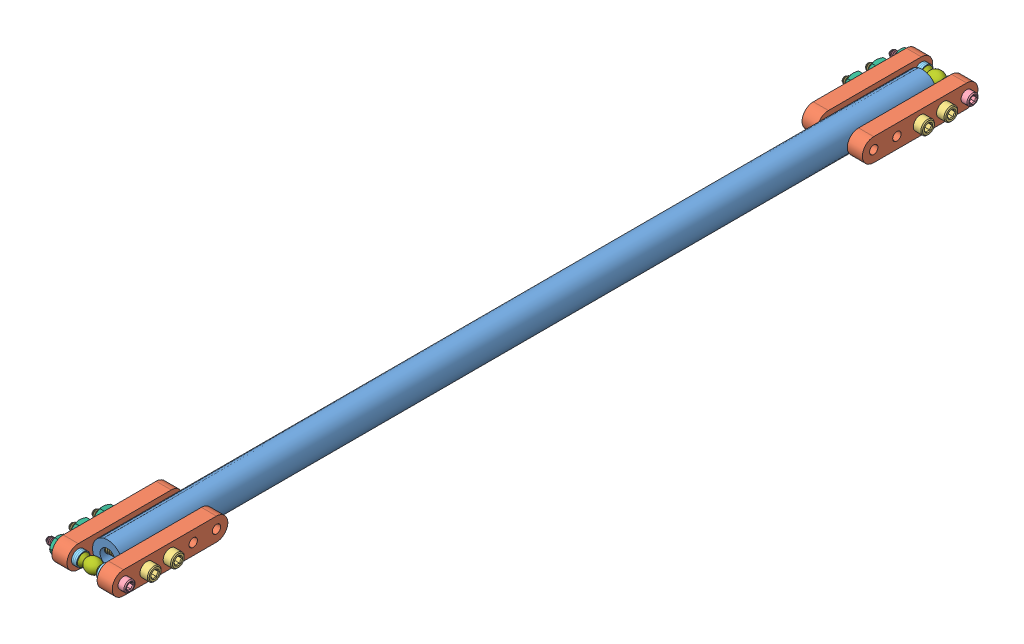
SolidWorks assembly Diff Pivot Top, configuration Default. Lengths in mm.
Overall size (35.29 12.7 364.36).
31 component instances, 7 part files, 34 mates.
Components (placement in the parent):
- 13.5 Inch Aluminum Rod-1: 13.5 Inch Aluminum Rod [Default] at (112.518 164.0173 110.0632) size (12.7 12.7 342.9)
- 5 Hole Aluminum Beam-1: 5 Hole Aluminum Beam [Default] at (106.168 164.0173 439.3742) x (0 0 -1) z (0 1 0) size (48.64 6.35 9.53)
- 5 Hole Aluminum Beam-2: 5 Hole Aluminum Beam [Default] at (125.218 164.0173 439.3742) x (0 0 -1) z (0 1 0) size (48.64 6.35 9.53)
- 6-32_SHCS-1: 6-32_SHCS [6-32 SHCS X 1.250] at (93.468 164.0173 449.1532) x (0 0 -1) z (1 0 0) size (5.74 5.74 35.26)
- 6-32_SHCS-2: 6-32_SHCS [6-32 SHCS X 1.250] at (93.468 164.0173 439.3742) x (0 0 -1) z (1 0 0) size (5.74 5.74 35.26)
- 4-40_SHCS-1: 4-40_SHCS [4-40 SHCS X 1.250] at (93.468 164.0173 458.9322) x (0 -0.924225 -0.381849) z (1 0 0) size (4.65 4.65 34.63)
- 4-40 Washer-1: 4-40 Washer [Default] at (118.1568 164.0173 458.9322) x (0 -1 0) z (0 0 1) size (5.71 0.71 5.71)
- 4-40 Washer-2: 4-40 Washer [Default] at (118.1568 164.0173 458.9322) x (0 1 0) z (0 0 1) size (5.71 0.71 5.71)
- 4-40 Washer-3: 4-40 Washer [Default] at (116.7344 164.0173 458.9322) x (0 -1 0) z (0 0 1) size (5.71 0.71 5.71)
- 4-40 Washer-4: 4-40 Washer [Default] at (106.168 164.0173 458.9322) x (0 -1 0) z (0 0 1) size (5.71 0.71 5.71)
- 4-40 Washer-5: 4-40 Washer [Default] at (107.5904 164.0173 458.9322) x (0 -1 0) z (0 0 1) size (5.71 0.71 5.71)
- 4-40 Washer-6: 4-40 Washer [Default] at (106.8792 164.0173 458.9322) x (0 -1 0) z (0 0 1) size (5.71 0.71 5.71)
- hex_nut-1: hex_nut [#6-32] at (99.818 164.0173 449.1532) x (0 1 0) z (0 0 1) size (7.92 2.9 10.06)
- hex_nut-2: hex_nut [#6-32] at (99.818 164.0173 439.3742) x (0 0.381849 -0.924225) z (0 0.924225 0.381849) size (7.92 2.9 10.06)
- hex_nut-3: hex_nut [#4-40] at (99.818 164.0173 458.9322) x (0 -0.381849 0.924225) z (0 -0.924225 -0.381849) size (6.35 2.49 8.06)
- 5 Hole Aluminum Beam-3: 5 Hole Aluminum Beam [Default] at (99.818 164.0173 123.6522) x (0 0 1) z (0 1 0) size (48.64 6.35 9.53)
- 5 Hole Aluminum Beam-4: 5 Hole Aluminum Beam [Default] at (118.868 164.0173 123.6522) x (0 0 1) z (0 1 0) size (48.64 6.35 9.53)
- 6-32_SHCS-3: 6-32_SHCS [6-32 SHCS X 1.250] at (93.468 164.0173 113.8732) x (0 0 -1) z (1 0 0) size (5.74 5.74 35.26)
- 6-32_SHCS-4: 6-32_SHCS [6-32 SHCS X 1.250] at (93.468 164.0173 123.6522) x (0 0 -1) z (1 0 0) size (5.74 5.74 35.26)
- 4-40_SHCS-2: 4-40_SHCS [4-40 SHCS X 1.250] at (93.468 164.0173 104.0942) x (0 0.924225 -0.381849) z (1 0 0) size (4.65 4.65 34.63)
- 4-40 Washer-7: 4-40 Washer [Default] at (118.1568 164.0173 104.0942) x (0 -1 0) z (0 0 1) size (5.71 0.71 5.71)
- 4-40 Washer-8: 4-40 Washer [Default] at (118.1568 164.0173 104.0942) x (0 1 0) z (0 0 1) size (5.71 0.71 5.71)
- 4-40 Washer-9: 4-40 Washer [Default] at (116.7344 164.0173 104.0942) x (0 -1 0) z (0 0 1) size (5.71 0.71 5.71)
- 4-40 Washer-10: 4-40 Washer [Default] at (106.168 164.0173 104.0942) x (0 -1 0) z (0 0 1) size (5.71 0.71 5.71)
- 4-40 Washer-11: 4-40 Washer [Default] at (107.5904 164.0173 104.0942) x (0 -1 0) z (0 0 1) size (5.71 0.71 5.71)
- 4-40 Washer-12: 4-40 Washer [Default] at (106.8792 164.0173 104.0942) x (0 -1 0) z (0 0 1) size (5.71 0.71 5.71)
- hex_nut-4: hex_nut [#6-32] at (99.818 164.0173 113.8732) x (0 1 0) z (0 0 1) size (7.92 2.9 10.06)
- hex_nut-5: hex_nut [#4-40] at (99.818 164.0173 104.0942) x (0 -0.381849 -0.924225) z (0 0.924225 -0.381849) size (6.35 2.49 8.06)
- hex_nut-6: hex_nut [#6-32] at (99.818 164.0173 123.6522) x (0 0.381849 0.924225) z (0 -0.924225 0.381849) size (7.92 2.9 10.06)
- Ball bearing-1: Ball bearing [Default] at (116.6455 164.0173 458.9322) x (0 1 0) z (0 0 1) size (5.73 8.26 5.73)
- Ball bearing-2: Ball bearing [Default] at (108.3905 164.0173 104.0942) x (0 -1 0) z (0 0 1) size (5.73 8.26 5.73)
Mates (geometry in assembly coordinates):
- Concentric3: concentric anti-aligned: cylinder of 13.5 Inch Aluminum Rod-1 through (-65.282 164.0173 439.3742) axis (1 0 0) radius 1.905; cylinder of 5 Hole Aluminum Beam-2 through (118.868 164.0173 439.3742) axis (-1 0 0) radius 1.778
- Concentric4: concentric anti-aligned: cylinder of 13.5 Inch Aluminum Rod-1 through (-65.282 164.0173 439.3742) axis (1 0 0) radius 1.905; cylinder of 5 Hole Aluminum Beam-1 through (99.818 164.0173 439.3742) axis (-1 0 0) radius 1.778
- Concentric5: concentric anti-aligned: cylinder of 13.5 Inch Aluminum Rod-1 through (-65.282 164.0173 439.3742) axis (1 0 0) radius 1.905; cylinder of 6-32_SHCS-2 through (137.918 164.0173 439.3742) axis (-1 0 0) radius 2.8702
- Concentric6: concentric aligned: cylinder of 5 Hole Aluminum Beam-1 through (99.818 164.0173 439.3742) axis (-1 0 0) radius 1.778; cylinder of hex_nut-2 through (98.1544 164.0173 439.3742) axis (-1 0 0) radius 1.323
- Concentric7: concentric anti-aligned: cylinder of 13.5 Inch Aluminum Rod-1 through (-65.282 164.0173 449.1532) axis (1 0 0) radius 1.905; cylinder of 5 Hole Aluminum Beam-1 through (99.818 164.0173 449.1532) axis (-1 0 0) radius 1.778
- Concentric8: concentric anti-aligned: cylinder of 13.5 Inch Aluminum Rod-1 through (-65.282 164.0173 449.1532) axis (1 0 0) radius 1.905; cylinder of 5 Hole Aluminum Beam-2 through (118.868 164.0173 449.1532) axis (-1 0 0) radius 1.778
- Concentric9: concentric anti-aligned: cylinder of 13.5 Inch Aluminum Rod-1 through (-65.282 164.0173 449.1532) axis (1 0 0) radius 1.905; cylinder of 6-32_SHCS-1 through (137.918 164.0173 449.1532) axis (-1 0 0) radius 2.8702
- Concentric10: concentric aligned: cylinder of 13.5 Inch Aluminum Rod-1 through (-65.282 164.0173 449.1532) axis (1 0 0) radius 1.905; cone of hex_nut-1 through (97.5177 164.0173 449.1532) axis (1 0 0)
- Tangent1: tangent anti-aligned: cylinder of 13.5 Inch Aluminum Rod-1 through (112.518 164.0173 452.9632) axis (0 0 -1) radius 6.35; plane of 5 Hole Aluminum Beam-1 through (106.168 164.0173 458.9322) normal (1 0 0)
- Tangent3: tangent anti-aligned: cylinder of 13.5 Inch Aluminum Rod-1 through (112.518 164.0173 452.9632) axis (0 0 -1) radius 6.35; plane of 5 Hole Aluminum Beam-2 through (118.868 164.0173 458.9322) normal (-1 0 0)
- Coincident1: coincident aligned: plane of 6-32_SHCS-2 through (125.218 164.0173 439.3742) normal (-1 0 0); plane of 6-32_SHCS-1 through (125.218 164.0173 449.1532) normal (-1 0 0)
- Coincident2: coincident anti-aligned: plane of 6-32_SHCS-2 through (125.218 164.0173 439.3742) normal (-1 0 0); plane of 5 Hole Aluminum Beam-2 through (125.218 164.0173 458.9322) normal (1 0 0)
- Coincident3: coincident anti-aligned: plane of 5 Hole Aluminum Beam-1 through (99.818 164.0173 458.9322) normal (-1 0 0); plane of hex_nut-2 through (99.818 156.1613 440.4157) normal (1 0 0)
- Coincident4: coincident anti-aligned: plane of 5 Hole Aluminum Beam-1 through (99.818 164.0173 458.9322) normal (-1 0 0); plane of hex_nut-1 through (99.818 160.0549 442.2902) normal (1 0 0)
- Concentric12: concentric aligned: cylinder of 5 Hole Aluminum Beam-2 through (118.868 164.0173 458.9322) axis (-1 0 0) radius 1.778; cylinder of 4-40 Washer-2 through (117.4456 164.0173 458.9322) axis (-1 0 0) radius 1.4732
- Concentric13: concentric anti-aligned: cylinder of 5 Hole Aluminum Beam-2 through (118.868 164.0173 458.9322) axis (-1 0 0) radius 1.778; cylinder of 4-40 Washer-6 through (107.5904 164.0173 458.9322) axis (1 0 0) radius 1.4732
- Concentric14: concentric anti-aligned: cylinder of 5 Hole Aluminum Beam-2 through (118.868 164.0173 458.9322) axis (-1 0 0) radius 1.778; cylinder of 4-40 Washer-4 through (106.8792 164.0173 458.9322) axis (1 0 0) radius 1.4732
- Concentric15: concentric anti-aligned: cylinder of 5 Hole Aluminum Beam-2 through (118.868 164.0173 458.9322) axis (-1 0 0) radius 1.778; cylinder of 4-40 Washer-5 through (108.3016 164.0173 458.9322) axis (1 0 0) radius 1.4732
- Concentric16: concentric anti-aligned: cylinder of 5 Hole Aluminum Beam-2 through (118.868 164.0173 458.9322) axis (-1 0 0) radius 1.778; cylinder of 4-40 Washer-3 through (117.4456 164.0173 458.9322) axis (1 0 0) radius 1.4732
- Concentric17: concentric anti-aligned: cylinder of 5 Hole Aluminum Beam-2 through (118.868 164.0173 458.9322) axis (-1 0 0) radius 1.778; cylinder of 4-40 Washer-1 through (118.868 164.0173 458.9322) axis (1 0 0) radius 1.4732
- Concentric19: concentric aligned: cylinder of 5 Hole Aluminum Beam-2 through (118.868 164.0173 458.9322) axis (-1 0 0) radius 1.778; cylinder of hex_nut-3 through (98.1544 164.0173 458.9322) axis (-1 0 0) radius 1.0787
- Coincident5: coincident anti-aligned: plane of 5 Hole Aluminum Beam-2 through (125.218 164.0173 458.9322) normal (1 0 0); plane of 4-40_SHCS-1 through (125.218 164.0173 458.9322) normal (-1 0 0)
- Coincident6: coincident anti-aligned: plane of 5 Hole Aluminum Beam-1 through (99.818 164.0173 458.9322) normal (-1 0 0); plane of hex_nut-3 through (99.818 167.4057 460.3322) normal (1 0 0)
- Coincident7: coincident anti-aligned: plane of 4-40 Washer-4 through (106.8792 164.0173 458.9322) normal (1 0 0); plane of 4-40 Washer-6 through (106.8792 164.0173 458.9322) normal (-1 0 0)
- Coincident8: coincident aligned: circle of 4-40 Washer-5; plane of 4-40 Washer-6 through (107.5904 164.0173 458.9322) normal (1 0 0)
- Coincident9: coincident anti-aligned: plane of 4-40 Washer-1 through (118.1568 164.0173 458.9322) normal (-1 0 0); plane of 4-40 Washer-2 through (118.1568 164.0173 458.9322) normal (1 0 0)
- Coincident10: coincident anti-aligned: plane of 4-40 Washer-2 through (117.4456 164.0173 458.9322) normal (-1 0 0); plane of 4-40 Washer-3 through (117.4456 164.0173 458.9322) normal (1 0 0)
- Coincident11: coincident anti-aligned: plane of 5 Hole Aluminum Beam-2 through (118.868 164.0173 458.9322) normal (-1 0 0); plane of 4-40 Washer-1 through (118.868 164.0173 458.9322) normal (1 0 0)
- Coincident12: coincident anti-aligned: plane of 5 Hole Aluminum Beam-1 through (106.168 164.0173 458.9322) normal (1 0 0); plane of 4-40 Washer-4 through (106.168 164.0173 458.9322) normal (-1 0 0)
- Concentric20: concentric anti-aligned: circle of 5 Hole Aluminum Beam-2; cylinder of 4-40_SHCS-1 through (137.918 164.0173 458.9322) axis (-1 0 0) radius 2.3241
- Coincident13: coincident anti-aligned: plane of Ball bearing-1; plane of assembly through (112.518 0 0) normal (1 0 0)
- Coincident14: coincident anti-aligned: plane of Ball bearing-1; plane of Ball bearing-2
- Concentric21: concentric anti-aligned: cylinder of 4-40_SHCS-2 through (137.918 164.0173 104.0942) axis (-1 0 0) radius 2.3241; cylinder of Ball bearing-2 through (116.3915 164.0173 104.0942) axis (1 0 0) radius 1.016
- Concentric22: concentric aligned: cylinder of 4-40_SHCS-1 through (137.918 164.0173 458.9322) axis (-1 0 0) radius 2.3241; cylinder of Ball bearing-1 through (108.6445 164.0173 458.9322) axis (-1 0 0) radius 1.016
